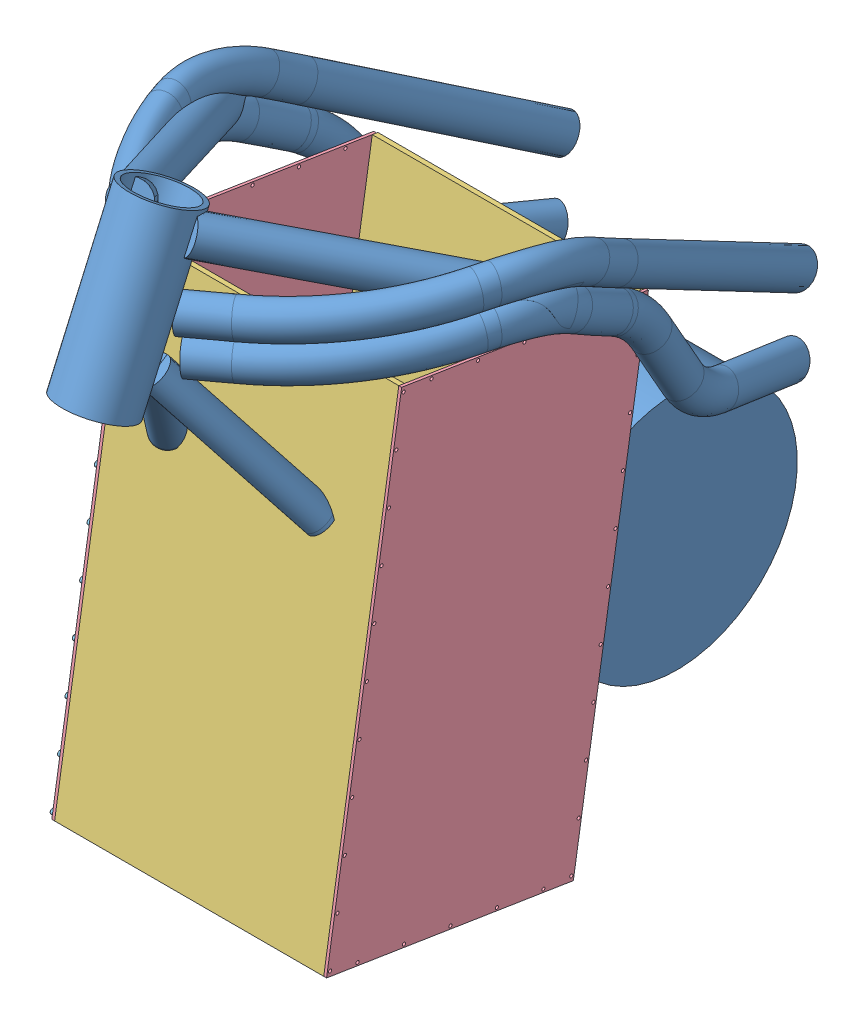
SolidWorks assembly FrameAndBattery, configuration Default. Lengths in mm.
Overall size (417.27 2274.43 2919.42).
18 component instances, 5 part files, 3 mates.
Components (placement in the parent):
- Frame Reference-1: Frame Reference [Default] at origin size (417.27 2274.43 2919.42)
- Enclosure_assy-2: Enclosure_assy [Default] at (-143 183.9921 -909.0911) x (0 0.156434 0.987688) z (-1 0 0) size (267.75 510 294.99)
  - Enclosure_Bottom-1: Enclosure_Bottom [Default] at origin size (255 5.99 286)
  - Enclosure_Front_Rear-1: Enclosure_Front_Rear [Default] at (0 0 -286) x (0 0 1) z (-1 0 0) size (286 510 5.99)
  - Enclosure_Front_Rear-2: Enclosure_Front_Rear [Default] at (255 0 0) x (0 0 -1) z (1 0 0) size (286 510 5.99)
  - Enclosure_Side-1: Enclosure_Side [Default] at (-4.5456 0 -288.9972) size (265.54 510 3)
  - Enclosure_Side-2: Enclosure_Side [Default] at (-4.5456 0 0) size (265.54 510 3)
  - socket head cap screw_am-1: socket head cap screw_am [B18.3.1M - 3 x 0.5 x 25 Hex SHCS -- 18NHX] at (257.9944 505 5.9972) x (0 0 -1) z (0.866025 -0.5 0) size (28 5.5 5.5)
  - socket head cap screw_am-2: socket head cap screw_am [B18.3.1M - 3 x 0.5 x 25 Hex SHCS -- 18NHX] at (257.9944 455 5.9972) x (0 0 -1) z (0.866025 -0.5 0) size (28 5.5 5.5)
  - socket head cap screw_am-3: socket head cap screw_am [B18.3.1M - 3 x 0.5 x 25 Hex SHCS -- 18NHX] at (257.9944 405 5.9972) x (0 0 -1) z (0.866025 -0.5 0) size (28 5.5 5.5)
  - socket head cap screw_am-4: socket head cap screw_am [B18.3.1M - 3 x 0.5 x 25 Hex SHCS -- 18NHX] at (257.9944 355 5.9972) x (0 0 -1) z (0.866025 -0.5 0) size (28 5.5 5.5)
  - socket head cap screw_am-5: socket head cap screw_am [B18.3.1M - 3 x 0.5 x 25 Hex SHCS -- 18NHX] at (257.9944 305 5.9972) x (0 0 -1) z (0.866025 -0.5 0) size (28 5.5 5.5)
  - socket head cap screw_am-6: socket head cap screw_am [B18.3.1M - 3 x 0.5 x 25 Hex SHCS -- 18NHX] at (257.9944 255 5.9972) x (0 0 -1) z (0.866025 -0.5 0) size (28 5.5 5.5)
  - socket head cap screw_am-7: socket head cap screw_am [B18.3.1M - 3 x 0.5 x 25 Hex SHCS -- 18NHX] at (257.9944 205 5.9972) x (0 0 -1) z (0.866025 -0.5 0) size (28 5.5 5.5)
  - socket head cap screw_am-8: socket head cap screw_am [B18.3.1M - 3 x 0.5 x 25 Hex SHCS -- 18NHX] at (257.9944 155 5.9972) x (0 0 -1) z (0.866025 -0.5 0) size (28 5.5 5.5)
  - socket head cap screw_am-9: socket head cap screw_am [B18.3.1M - 3 x 0.5 x 25 Hex SHCS -- 18NHX] at (257.9944 105 5.9972) x (0 0 -1) z (0.866025 -0.5 0) size (28 5.5 5.5)
  - socket head cap screw_am-10: socket head cap screw_am [B18.3.1M - 3 x 0.5 x 25 Hex SHCS -- 18NHX] at (257.9944 55 5.9972) x (0 0 -1) z (0.866025 -0.5 0) size (28 5.5 5.5)
  - socket head cap screw_am-11: socket head cap screw_am [B18.3.1M - 3 x 0.5 x 25 Hex SHCS -- 18NHX] at (257.9944 5 5.9972) x (0 0 -1) z (0.866025 -0.5 0) size (28 5.5 5.5)
Mates (geometry in assembly coordinates):
- Parallel3: parallel: plane of assembly through (0 0 0) normal (1 0 0); plane of Enclosure_assy-2/Enclosure_Side-2 through (-145.9972 183.2811 -913.5807) normal (-1 0 0); plane of assembly
- Angle1: planar angle = 0.15708 rad: plane of assembly through (0 0 0) normal (0 0 1); plane of Enclosure_assy-2/Enclosure_Front_Rear-2 through (-143 224.8207 -651.31) normal (0 0.156434 0.987688); plane of assembly
- Coincident8: coincident: point of assembly; moEndPointRef_w of Enclosure_assy-2/Enclosure_Front_Rear-1; plane of assembly
